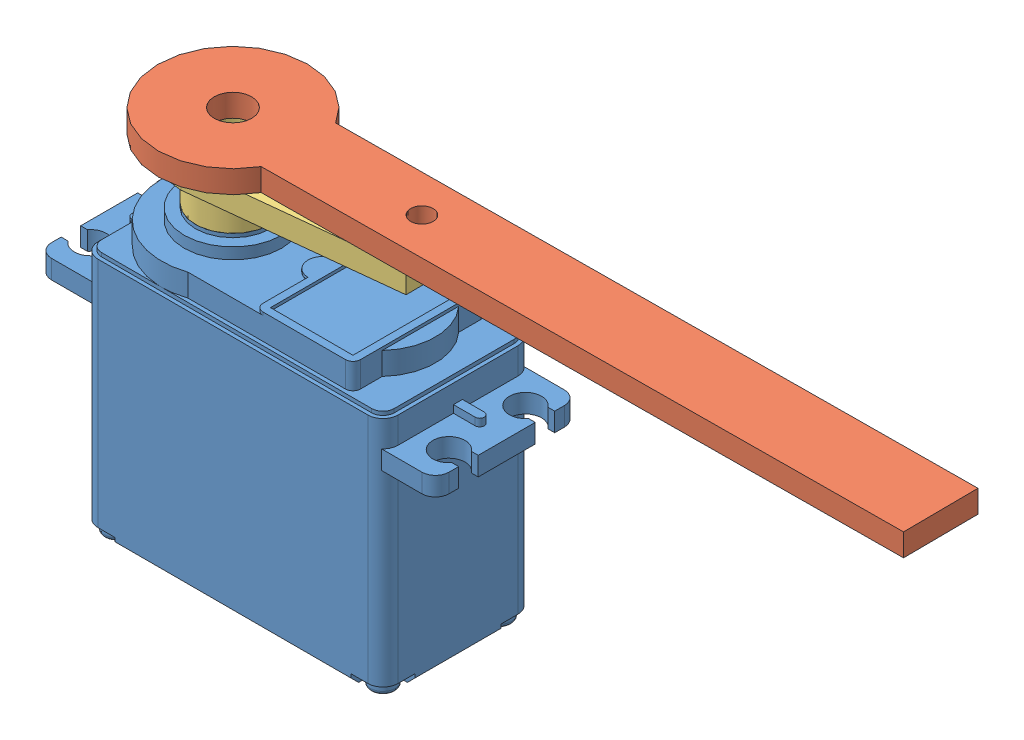
SolidWorks assembly MirrorAssem5, configuration Default. Lengths in mm.
Overall size (110.23 49.02 20.79).
3 component instances, 3 part files, 5 mates.
Components (placement in the parent):
- MirrorServo-D-1: MirrorServo-D [По умолчанию] at (11.6826 13.0222 -54.9003) size (53 41.52 20)
- Mirror1--1: Mirror1- [Default] at (1.6826 59.0222 -54.9003) x (-0.999971 0 0.00759) z (0 -1 0) size (103.66 20 3)
- Mirror2__-1: Mirror2__ [Default] at (1.6826 51.0222 -54.9003) x (-0.999971 0 0.00759) z (0 -1 0) size (34.13 14 8)
Mates (geometry in assembly coordinates):
- Concentric1: concentric aligned: cylinder of MirrorServo-D-1 through (1.6826 54.5222 -54.9003) axis (0 -1 0) radius 3; cylinder of Mirror2__-1 through (1.6826 56.0222 -54.9003) axis (0 -1 0) radius 3
- Concentric2: concentric aligned: cylinder of Mirror1--1 through (1.6826 62.0222 -54.9003) axis (0 -1 0) radius 2.5; cylinder of Mirror2__-1 through (1.6826 56.0222 -54.9003) axis (0 -1 0) radius 3
- Coincident1: coincident anti-aligned: plane of Mirror1--1 through (1.6826 59.0222 -54.9003) normal (0 -1 0); plane of Mirror2__-1 through (31.6817 59.0222 -55.128) normal (0 1 0)
- Coincident2: coincident anti-aligned: plane of MirrorServo-D-1 through (1.6826 51.0222 -54.9003) normal (0 1 0); plane of Mirror2__-1 through (1.6826 51.0222 -54.9003) normal (0 -1 0)
- Width1: width anti-aligned: plane of Mirror1--1 through (95.3022 62.0222 -60.611) normal (-0.00759 0 -0.999971); plane of Mirror2__-1 through (95.3781 62.0222 -50.6113) normal (0.00759 0 0.999971); plane of Mirror1--1 through (31.6514 59.0222 -59.1279) normal (0.091948 0 -0.995764); plane of Mirror2__-1 through (31.7121 59.0222 -51.1281) normal (0.107053 0 0.994253)
